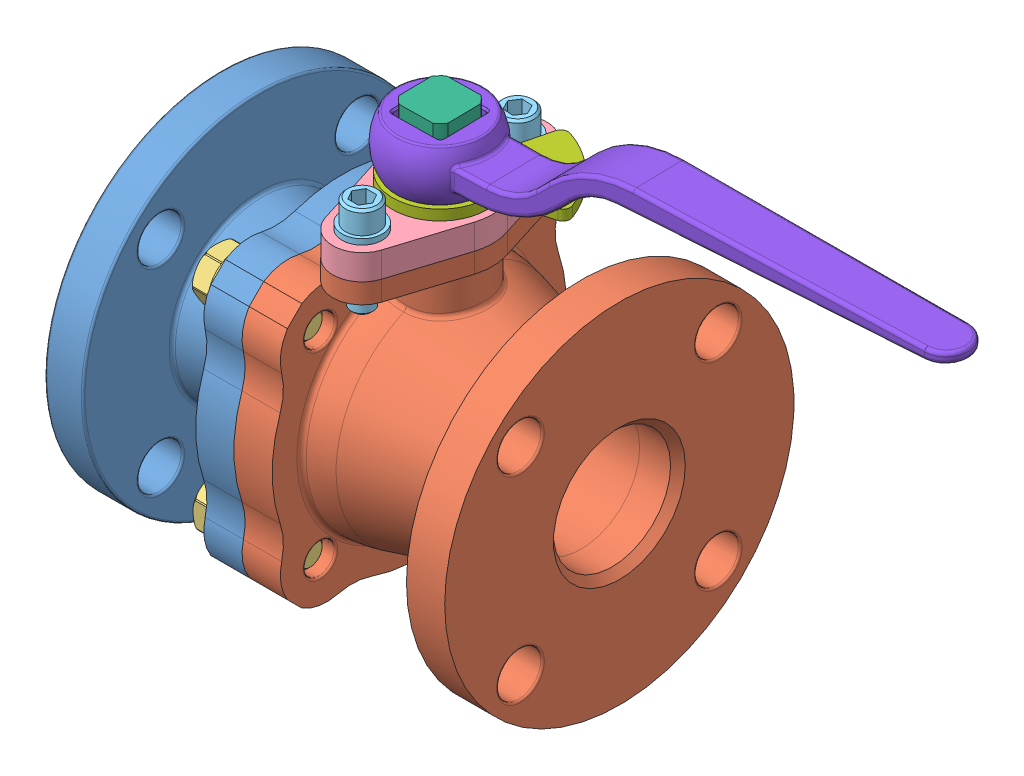
SolidWorks assembly Assembly, configuration Default. Lengths in mm.
Overall size (320.96 206.39 152.4).
12 component instances, 8 part files, 27 mates.
Components (placement in the parent):
- 1 Outer Housing-1: 1 Outer Housing [Default] at (-137.1456 35.679 241.2072) size (70.48 152.4 152.4)
- 2 Inlet Housing-1: 2 Inlet Housing [Default] at (-137.1456 35.679 241.2072) size (102.87 150.77 150.77)
- 7 Hex Bolt-1: 7 Hex Bolt [Default] at (-101.0043 78.3352 283.8634) x (0 0 -1) z (1 0 0) size (24.51 24.51 41.54)
- 7 Hex Bolt-2: 7 Hex Bolt [Default] at (-101.0043 -6.9772 283.8634) x (0 0.536538 -0.843876) z (1 0 0) size (24.51 24.51 41.54)
- 7 Hex Bolt-4: 7 Hex Bolt [Default] at (-101.0043 78.3352 198.551) x (0 0.674924 -0.737887) z (1 0 0) size (24.51 24.51 41.54)
- 7 Hex Bolt-6: 7 Hex Bolt [Default] at (-101.0043 -6.9772 198.551) x (0 0.792804 -0.609477) z (1 0 0) size (24.51 24.51 41.54)
- 3 ThermoStat Flange-1: 3 ThermoStat Flange [Default] at (-137.1456 35.679 241.2072) size (45.54 10.92 92.46)
- 6 Cap Screw-1: 6 Cap Screw [Default] at (-61.4312 75.5334 274.7352) x (1 0 0) z (0 -1 0) size (17.35 17.35 41.27)
- 6 Cap Screw-2: 6 Cap Screw [Default] at (-61.4312 75.5334 207.6792) x (0.546944 0 -0.837169) z (0 -1 0) size (17.35 17.35 41.27)
- 4 Ball Valve Sub-1: 4 Ball Valve Sub [Default] at (-61.4312 75.1495 241.2072) x (-0.016753 0 -0.99986) z (0 -1 0) size (50.8 33.6 137.67)
- 5 Lock Lever-1: 5 Lock Lever [Default] at (-61.3878 116.959 241.2491) x (0.99986 0 -0.016753) z (0.016753 0 0.99986) size (62.42 4.45 62.42)
- 8 Handle-1: 8 Handle [Default] at (-20.436 137.3425 240.563) x (0.99986 0 -0.016753) z (0 -1 0) size (246.38 43.18 48.26)
Mates (geometry in assembly coordinates):
- Coincident1: coincident anti-aligned: plane of 1 Outer Housing-1 through (-86.8312 10.279 241.2072) normal (1 0 0); plane of 2 Inlet Housing-1 through (-86.8312 77.6985 255.7043) normal (-1 0 0)
- Concentric1: concentric anti-aligned: cylinder of 1 Outer Housing-1 through (-103.3412 78.3352 283.8634) axis (1 0 0) radius 6.6675; cylinder of 2 Inlet Housing-1 through (-70.3212 78.3352 283.8634) axis (-1 0 0) radius 6.6675
- Concentric2: concentric anti-aligned: cylinder of 1 Outer Housing-1 through (-103.3412 78.3352 283.8634) axis (1 0 0) radius 6.6675; cylinder of 7 Hex Bolt-1 through (-125.8968 78.3352 283.8634) axis (-1 0 0) radius 6.35
- Coincident2: coincident anti-aligned: plane of 1 Outer Housing-1 through (-103.3412 -19.7901 241.2072) normal (-1 0 0); plane of 7 Hex Bolt-1 through (-103.3412 78.3352 290.2134) normal (1 0 0)
- Concentric3: concentric aligned: cylinder of 2 Inlet Housing-1 through (-70.3212 -6.9772 283.8634) axis (-1 0 0) radius 6.6675; cylinder of 7 Hex Bolt-2 through (-125.8968 -6.9772 283.8634) axis (-1 0 0) radius 6.35
- Coincident3: coincident anti-aligned: plane of 1 Outer Housing-1 through (-103.3412 -19.7901 241.2072) normal (-1 0 0); plane of 7 Hex Bolt-2 through (-103.3412 -10.3842 289.222) normal (1 0 0)
- Concentric4: concentric aligned: cylinder of 2 Inlet Housing-1 through (-70.3212 78.3352 198.551) axis (-1 0 0) radius 6.6675; cylinder of 7 Hex Bolt-4 through (-125.8968 78.3352 198.551) axis (-1 0 0) radius 6.35
- Coincident4: coincident anti-aligned: plane of 1 Outer Housing-1 through (-103.3412 -19.7901 241.2072) normal (-1 0 0); plane of 7 Hex Bolt-4 through (-103.3412 74.0495 203.2366) normal (1 0 0)
- Concentric5: concentric aligned: cylinder of 2 Inlet Housing-1 through (-70.3212 -6.9772 198.551) axis (-1 0 0) radius 6.6675; cylinder of 7 Hex Bolt-6 through (-125.8968 -6.9772 198.551) axis (-1 0 0) radius 6.35
- Coincident5: coincident anti-aligned: plane of 1 Outer Housing-1 through (-103.3412 -19.7901 241.2072) normal (-1 0 0); plane of 7 Hex Bolt-6 through (-103.3412 -12.0115 202.4212) normal (1 0 0)
- Coincident6: coincident anti-aligned: plane of 2 Inlet Housing-1 through (-137.1456 105.529 241.2072) normal (0 1 0); plane of 3 ThermoStat Flange-1 through (-61.4312 105.529 274.7352) normal (0 -1 0)
- Concentric6: concentric anti-aligned: cylinder of 2 Inlet Housing-1 through (-61.4312 -39.7092 241.2072) axis (0 1 0) radius 12.7; cylinder of 3 ThermoStat Flange-1 through (-61.4312 116.451 241.2072) axis (0 -1 0) radius 12.7
- Concentric7: concentric anti-aligned: cylinder of 3 ThermoStat Flange-1 through (-61.4312 116.451 274.7352) axis (0 -1 0) radius 4.826; cylinder of 6 Cap Screw-1 through (-61.4312 162.1367 274.7352) axis (0 1 0) radius 4.7625
- Coincident7: coincident anti-aligned: plane of 3 ThermoStat Flange-1 through (-61.4312 116.451 274.7352) normal (0 1 0); plane of 6 Cap Screw-1 through (-66.1937 116.451 274.7352) normal (0 -1 0)
- Concentric8: concentric aligned: cylinder of 2 Inlet Housing-1 through (-61.4312 96.9438 207.6792) axis (0 1 0) radius 4.826; cylinder of 6 Cap Screw-2 through (-61.4312 162.1367 207.6792) axis (0 1 0) radius 4.7625
- Coincident8: coincident anti-aligned: plane of 3 ThermoStat Flange-1 through (-61.4312 116.451 274.7352) normal (0 1 0); plane of 6 Cap Screw-2 through (-64.036 116.451 211.6662) normal (0 -1 0)
- Concentric9: concentric aligned: cylinder of 2 Inlet Housing-1 through (-61.4312 -39.7092 241.2072) axis (0 1 0) radius 12.7; cylinder of 4 Ball Valve Sub-1 through (-61.4312 127.5941 241.2072) axis (0 1 0) radius 12.7
- Concentric10: concentric anti-aligned: cylinder of 1 Outer Housing-1 through (-103.3412 75.684 201.2022) axis (1 0 0) radius 19.9898; cylinder of 2 Inlet Housing-1 through (-70.3212 75.684 201.2022) axis (-1 0 0) radius 19.9898
- Tangent1: tangent aligned: cylinder of 2 Inlet Housing-1 through (-70.3212 35.679 241.2072) axis (-1 0 0) radius 25.4; sphere of 4 Ball Valve Sub-1
- Coincident9: coincident anti-aligned: plane of 4 Ball Valve Sub-1 through (-54.368 116.959 230.6525) normal (-0.016753 0 -0.99986); plane of 5 Lock Lever-1 through (-71.0235 121.404 230.9316) normal (0.016753 0 0.99986)
- Coincident10: coincident anti-aligned: plane of 4 Ball Valve Sub-1 through (-71.9859 116.959 234.144) normal (-0.99986 0 0.016753); plane of 5 Lock Lever-1 through (-71.7054 121.404 250.8848) normal (0.99986 0 -0.016753)
- Coincident12: coincident anti-aligned: plane of 4 Ball Valve Sub-1 through (-61.4312 116.959 241.2072) normal (0 1 0); plane of 5 Lock Lever-1 through (-38.1327 116.959 237.9007) normal (0 -1 0)
- Coincident17: coincident anti-aligned: plane of 4 Ball Valve Sub-1 through (-51.119 116.959 233.7944) normal (0.99986 0 -0.016753); plane of 8 Handle-1 through (-51.1555 121.404 231.6148) normal (-0.99986 0 0.016753)
- Coincident18: coincident anti-aligned: plane of 4 Ball Valve Sub-1 through (-54.368 116.959 230.6525) normal (-0.016753 0 -0.99986); plane of 8 Handle-1 through (-52.1884 121.404 230.616) normal (0.016753 0 0.99986)
- Parallel3: parallel anti-aligned: cylinder of 5 Lock Lever-1 through (-38.6906 121.404 231.3425) axis (0 -1 0) radius 2.159; cylinder of 8 Handle-1 through (-38.863 117.6125 231.3454) axis (0 1 0) radius 1.905
- Coincident19: coincident anti-aligned: plane of 5 Lock Lever-1 through (-38.1327 121.404 237.9007) normal (0 1 0); plane of 8 Handle-1 through (-80.3427 121.404 219.9737) normal (0 -1 0)
- Parallel4: parallel anti-aligned: plane of 4 Ball Valve Sub-1 through (-61.4312 75.1495 241.2072) normal (-0.016753 0 -0.99986); plane of 8 Handle-1 through (-20.436 137.3425 240.563) normal (0.016753 0 0.99986)
